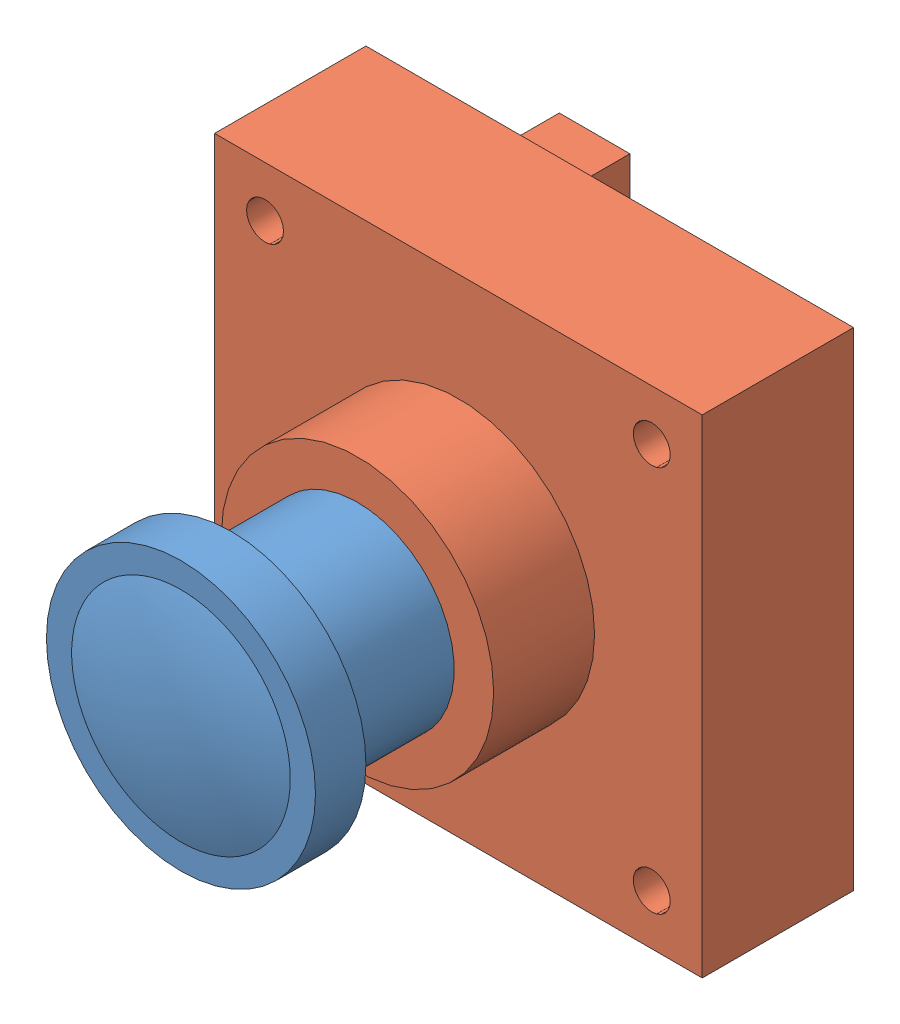
SolidWorks assembly basler_camera_160_assembly, configuration Default. Lengths in mm.
Overall size (29 29 31.6).
2 component instances, 2 part files, 3 mates.
Components (placement in the parent):
- basler_lens-1: basler_lens [Default] at (14.5 14.5 8.7) size (16 16 17.8)
- basler_body_160-1: basler_body_160 [Default] at origin size (29 29 20.1)
Mates (geometry in assembly coordinates):
- Coincident1: coordinate: point of basler_body_160-1
- Concentric1: concentric: cylinder of basler_lens-1 through (14.5 14.5 26.5) axis (0 0 -1) radius 5.75; cylinder of basler_body_160-1 through (14.5 14.5 9) axis (0 0 1) radius 5.75
- Distance1: distance = 16.5 mm aligned: plane of basler_body_160-1 through (0 0 9) normal (0 0 1); plane of basler_lens-1 through (14.5 14.5 25.5) normal (0 0 1)
